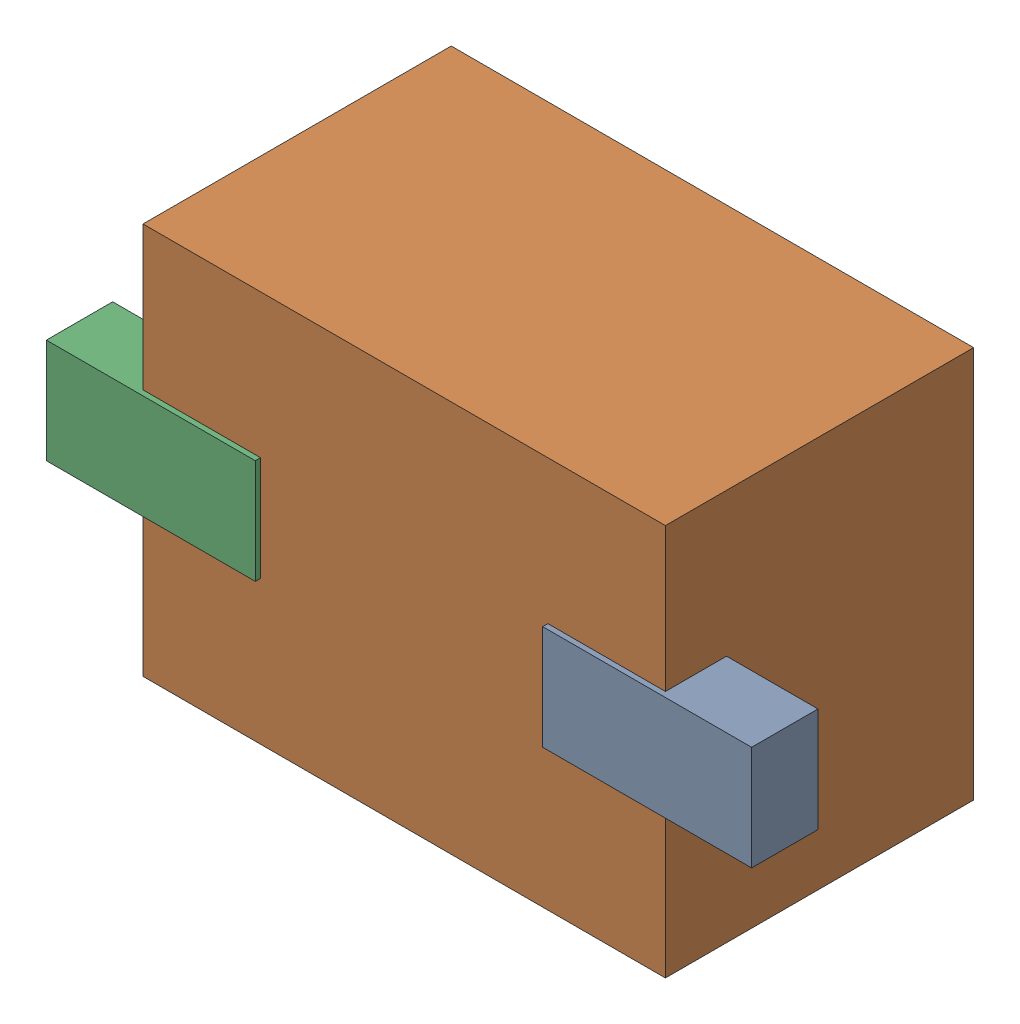
SolidWorks assembly D6, configuration Default. Lengths in mm.
Overall size (2.7 1.5 1.2).
6 component instances, 2 part files, 0 mates.
Components (placement in the parent):
- 710424080_2-1: 710424080_2 [Default] at (15.9 35 -0.6655) size (0.8 0.4 0.25)
  - Extruded (18)-1: Extruded (18) [Default] at origin size (0.8 0.4 0.25)
- 710423952_1-1: 710423952_1 [Default] at (14.95 35 -1.6115) size (2 1.5 1.18)
  - Extruded (19)-1: Extruded (19) [Default] at origin size (2 1.5 1.18)
- 710424080_3-1: 710424080_3 [Default] at (14 35 -0.6655) size (0.8 0.4 0.25)
  - Extruded (18)-1: Extruded (18) [Default] at origin size (0.8 0.4 0.25)
